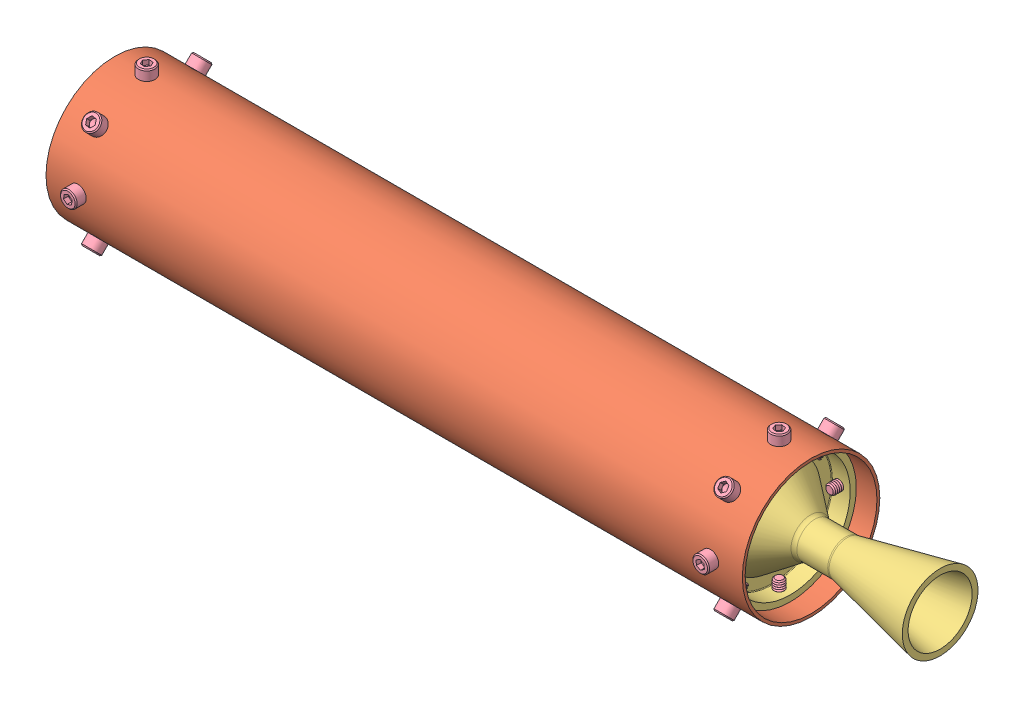
SolidWorks assembly Montagem1, configuration Valor predeterminado. Lengths in mm.
Overall size (286.03 54.66 54.66).
19 component instances, 4 part files, 37 mates.
Components (placement in the parent):
- Epoch Bulkhead-1: Epoch Bulkhead [Valor predeterminado] at (-185.2556 8.6887 45.5676) size (13.69 45.57 45.57)
- Epoch Casing-1: Epoch Casing [Valor predeterminado] at (-105.5307 8.6887 45.5676) size (241.3 47.65 47.65)
- Epoch Nozzle-1: Epoch Nozzle [Valor predeterminado] at (74.7918 8.6887 45.5676) size (67.13 45.67 45.67)
- socket head cap screw_ai632comespiral-2: socket head cap screw_ai632comespiral [HX-SHCS 0.138-32x0.25x0.25-S] at (34.2137 28.0142 64.8931) x (0 -0.707107 -0.707107) z (-0.36592 -0.658066 0.658066) size (9.86 5.74 5.74)
- socket head cap screw_ai632comespiral-3: socket head cap screw_ai632comespiral [HX-SHCS 0.138-32x0.25x0.25-S] at (-184.9375 28.0142 26.2421) x (0 -0.707107 0.707107) z (-0.707107 0.5 0.5) size (9.86 5.74 5.74)
- socket head cap screw_ai632comespiral-4: socket head cap screw_ai632comespiral [HX-SHCS 0.138-32x0.25x0.25-S] at (34.2137 8.6887 18.2372) x (0 0 1) z (-0.773525 -0.633766 0) size (9.86 5.74 5.74)
- socket head cap screw_ai632comespiral-5: socket head cap screw_ai632comespiral [HX-SHCS 0.138-32x0.25x0.25-S] at (34.2137 28.0142 26.2421) x (0 -0.707107 0.707107) z (-0.707107 0.5 0.5) size (9.86 5.74 5.74)
- socket head cap screw_ai632comespiral-6: socket head cap screw_ai632comespiral [HX-SHCS 0.138-32x0.25x0.25-S] at (34.2137 -18.6417 45.5676) x (0 1 0) z (-0.155936 0 0.987767) size (9.86 5.74 5.74)
- socket head cap screw_ai632comespiral-7: socket head cap screw_ai632comespiral [HX-SHCS 0.138-32x0.25x0.25-S] at (34.2137 36.0191 45.5676) x (0 -1 0) z (-0.163272 0 0.986581) size (9.86 5.74 5.74)
- socket head cap screw_ai632comespiral-8: socket head cap screw_ai632comespiral [HX-SHCS 0.138-32x0.25x0.25-S] at (34.2137 8.6887 72.898) x (0 0 -1) z (0.442421 0.896807 0) size (9.86 5.74 5.74)
- socket head cap screw_ai632comespiral-9: socket head cap screw_ai632comespiral [HX-SHCS 0.138-32x0.25x0.25-S] at (-184.9375 -18.6417 45.5676) x (0 1 0) z (-0.333471 0 0.94276) size (9.86 5.74 5.74)
- socket head cap screw_ai632comespiral-10: socket head cap screw_ai632comespiral [HX-SHCS 0.138-32x0.25x0.25-S] at (34.2137 -10.6368 26.2421) x (0 0.707107 0.707107) z (-0.686828 -0.513939 0.513939) size (9.86 5.74 5.74)
- socket head cap screw_ai632comespiral-11: socket head cap screw_ai632comespiral [HX-SHCS 0.138-32x0.25x0.25-S] at (34.2137 -10.6368 64.8931) x (0 0.707107 -0.707107) z (0.271558 0.680535 0.680535) size (9.86 5.74 5.74)
- socket head cap screw_ai632comespiral-12: socket head cap screw_ai632comespiral [HX-SHCS 0.138-32x0.25x0.25-S] at (-184.9375 -10.6368 64.8931) x (0 0.707107 -0.707107) z (-0.76182 0.458056 0.458056) size (9.86 5.74 5.74)
- socket head cap screw_ai632comespiral-13: socket head cap screw_ai632comespiral [HX-SHCS 0.138-32x0.25x0.25-S] at (-184.9375 -10.6368 26.2421) x (0 0.707107 0.707107) z (-0.814375 -0.410361 0.410361) size (9.86 5.74 5.74)
- socket head cap screw_ai632comespiral-14: socket head cap screw_ai632comespiral [HX-SHCS 0.138-32x0.25x0.25-S] at (-184.9375 8.6887 18.2372) x (0 0 1) z (-1 0 0) size (9.86 5.74 5.74)
- socket head cap screw_ai632comespiral-15: socket head cap screw_ai632comespiral [HX-SHCS 0.138-32x0.25x0.25-S] at (-184.9375 8.6887 72.898) x (0 0 -1) z (0.339206 -0.940712 0) size (9.86 5.74 5.74)
- socket head cap screw_ai632comespiral-16: socket head cap screw_ai632comespiral [HX-SHCS 0.138-32x0.25x0.25-S] at (-184.9375 28.0142 64.8931) x (0 -0.707107 -0.707107) z (-0.917285 -0.281592 0.281592) size (9.86 5.74 5.74)
- socket head cap screw_ai632comespiral-17: socket head cap screw_ai632comespiral [HX-SHCS 0.138-32x0.25x0.25-S] at (-184.9375 36.0191 45.5676) x (0 -1 0) z (-0.117759 0 0.993042) size (9.86 5.74 5.74)
Mates (geometry in assembly coordinates):
- Concêntrico1: concentric aligned: circle of Epoch Casing-1; circle of Epoch Nozzle-1
- Concêntrico2: concentric aligned: circle of Epoch Bulkhead-1; circle of Epoch Casing-1
- Concêntrico3: concentric aligned: cylinder of Epoch Casing-1 through (34.2137 32.5139 45.5676) axis (0 1 0) radius 1.3526; cylinder of Epoch Nozzle-1 through (34.2137 31.5233 45.5676) axis (0 1 0) radius 1.3526
- Concêntrico4: concentric aligned: cylinder of Epoch Bulkhead-1 through (-184.9375 31.4725 45.5676) axis (0 1 0) radius 1.3526; cylinder of Epoch Casing-1 through (-184.9375 32.5139 45.5676) axis (0 1 0) radius 1.3526
- Paralelo1: parallel aligned: plane of Epoch Casing-1 through (45.2881 32.5139 45.5676) normal (1 0 0); plane of Epoch Nozzle-1 through (38.1253 8.6887 45.5676) normal (1 0 0)
- Concêntrico6: concentric aligned: cylinder of Epoch Casing-1 through (34.2137 32.5139 45.5676) axis (0 1 0) radius 1.3526; cylinder of socket head cap screw_ai632comespiral-7 through (34.2137 67.7691 45.5676) axis (0 1 0) radius 1.7526
- Concêntrico8: concentric aligned: cylinder of Epoch Casing-1 through (34.2137 25.5357 28.7206) axis (0 0.707107 -0.707107) radius 1.3526; cylinder of socket head cap screw_ai632comespiral-5 through (34.2137 50.4649 3.7914) axis (0 0.707107 -0.707107) radius 1.7526
- Concêntrico10: concentric aligned: cylinder of Epoch Nozzle-1 through (34.2137 8.6887 22.733) axis (0 0 -1) radius 1.3526; cylinder of socket head cap screw_ai632comespiral-4 through (34.2137 8.6887 -13.5128) axis (0 0 -1) radius 1.7526
- Concêntrico12: concentric aligned: cylinder of Epoch Nozzle-1 through (34.2137 24.8352 61.7141) axis (0 0.707107 0.707107) radius 1.3526; cylinder of socket head cap screw_ai632comespiral-2 through (34.2137 50.4649 87.3438) axis (0 0.707107 0.707107) radius 1.7526
- Concêntrico14: concentric aligned: cylinder of Epoch Nozzle-1 through (34.2137 8.6887 68.4022) axis (0 0 1) radius 1.3526; cylinder of socket head cap screw_ai632comespiral-8 through (34.2137 8.6887 104.648) axis (0 0 1) radius 1.7526
- Concêntrico18: concentric aligned: cylinder of Epoch Nozzle-1 through (34.2137 -14.1459 45.5676) axis (0 -1 0) radius 1.3526; cylinder of socket head cap screw_ai632comespiral-6 through (34.2137 -50.3917 45.5676) axis (0 -1 0) radius 1.7526
- Concêntrico20: concentric aligned: cylinder of Epoch Nozzle-1 through (34.2137 -7.4578 29.4211) axis (0 -0.707107 -0.707107) radius 1.3526; cylinder of socket head cap screw_ai632comespiral-10 through (34.2137 -33.0874 3.7914) axis (0 -0.707107 -0.707107) radius 1.7526
- Tangente1: tangent anti-aligned: cylinder of Epoch Casing-1 through (-194.4327 8.6887 45.5676) axis (-1 0 0) radius 23.8252; plane of socket head cap screw_ai632comespiral-7 through (37.0454 32.5139 46.0362) normal (0 -1 0)
- Tangente2: tangent anti-aligned: cylinder of Epoch Casing-1 through (-194.4327 8.6887 45.5676) axis (-1 0 0) radius 23.8252; plane of socket head cap screw_ai632comespiral-2 through (36.8849 24.793 63.1572) normal (0 -0.707107 -0.707107)
- Tangente3: tangent anti-aligned: cylinder of Epoch Casing-1 through (-194.4327 8.6887 45.5676) axis (-1 0 0) radius 23.8252; plane of socket head cap screw_ai632comespiral-8 through (31.6397 9.9586 69.3928) normal (0 0 -1)
- Tangente5: tangent anti-aligned: cylinder of Epoch Casing-1 through (-194.4327 8.6887 45.5676) axis (-1 0 0) radius 23.8252; plane of socket head cap screw_ai632comespiral-6 through (31.3786 -15.1365 45.12) normal (0 1 0)
- Tangente6: tangent anti-aligned: cylinder of Epoch Casing-1 through (-194.4327 8.6887 45.5676) axis (-1 0 0) radius 23.8252; plane of socket head cap screw_ai632comespiral-10 through (32.1276 -6.7643 27.3267) normal (0 0.707107 0.707107)
- Tangente7: tangent anti-aligned: cylinder of Epoch Casing-1 through (-194.4327 8.6887 45.5676) axis (-1 0 0) radius 23.8252; plane of socket head cap screw_ai632comespiral-4 through (32.3947 10.9089 21.7424) normal (0 0 1)
- Tangente8: tangent anti-aligned: cylinder of Epoch Casing-1 through (-194.4327 8.6887 45.5676) axis (-1 0 0) radius 23.8252; plane of socket head cap screw_ai632comespiral-5 through (36.2433 26.9708 30.1557) normal (0 -0.707107 0.707107)
- Concêntrico23: concentric aligned: cylinder of Epoch Bulkhead-1 through (-184.9375 -7.4218 61.6782) axis (0 -0.707107 0.707107) radius 1.3526; cylinder of socket head cap screw_ai632comespiral-12 through (-184.9375 -33.0874 87.3438) axis (0 -0.707107 0.707107) radius 1.7526
- Concêntrico25: concentric aligned: cylinder of Epoch Bulkhead-1 through (-184.9375 -14.0951 45.5676) axis (0 -1 0) radius 1.3526; cylinder of socket head cap screw_ai632comespiral-9 through (-184.9375 -50.3917 45.5676) axis (0 -1 0) radius 1.7526
- Concêntrico27: concentric aligned: cylinder of Epoch Casing-1 through (-184.9375 -8.1582 28.7206) axis (0 -0.707107 -0.707107) radius 1.3526; cylinder of socket head cap screw_ai632comespiral-13 through (-184.9375 -33.0874 3.7914) axis (0 -0.707107 -0.707107) radius 1.7526
- Concêntrico29: concentric aligned: cylinder of Epoch Bulkhead-1 through (-184.9375 8.6887 22.7838) axis (0 0 -1) radius 1.3526; cylinder of socket head cap screw_ai632comespiral-14 through (-184.9375 8.6887 -13.5128) axis (0 0 -1) radius 1.7526
- Concêntrico31: concentric aligned: cylinder of Epoch Casing-1 through (-184.9375 25.5357 28.7206) axis (0 0.707107 -0.707107) radius 1.3526; cylinder of socket head cap screw_ai632comespiral-3 through (-184.9375 50.4649 3.7914) axis (0 0.707107 -0.707107) radius 1.7526
- Concêntrico33: concentric aligned: cylinder of Epoch Casing-1 through (-184.9375 32.5139 45.5676) axis (0 1 0) radius 1.3526; cylinder of socket head cap screw_ai632comespiral-17 through (-184.9375 67.7691 45.5676) axis (0 1 0) radius 1.7526
- Concêntrico35: concentric aligned: cylinder of Epoch Casing-1 through (-184.9375 25.5357 62.4146) axis (0 0.707107 0.707107) radius 1.3526; cylinder of socket head cap screw_ai632comespiral-16 through (-184.9375 50.4649 87.3438) axis (0 0.707107 0.707107) radius 1.7526
- Concêntrico37: concentric aligned: cylinder of Epoch Casing-1 through (-184.9375 8.6887 69.3928) axis (0 0 1) radius 1.3526; cylinder of socket head cap screw_ai632comespiral-15 through (-184.9375 8.6887 104.648) axis (0 0 1) radius 1.7526
- Tangente9: tangent anti-aligned: cylinder of Epoch Casing-1 through (-194.4327 8.6887 45.5676) axis (-1 0 0) radius 23.8252; plane of socket head cap screw_ai632comespiral-15 through (-182.2374 9.6623 69.3928) normal (0 0 -1)
- Tangente10: tangent anti-aligned: cylinder of Epoch Casing-1 through (-194.4327 8.6887 45.5676) axis (-1 0 0) radius 23.8252; plane of socket head cap screw_ai632comespiral-12 through (-186.7967 -9.7044 60.8684) normal (0 0.707107 -0.707107)
- Tangente11: tangent anti-aligned: cylinder of Epoch Casing-1 through (-194.4327 8.6887 45.5676) axis (-1 0 0) radius 23.8252; plane of socket head cap screw_ai632comespiral-9 through (-187.6434 -15.1365 44.6105) normal (0 1 0)
- Tangente12: tangent anti-aligned: cylinder of Epoch Casing-1 through (-194.4327 8.6887 45.5676) axis (-1 0 0) radius 23.8252; plane of socket head cap screw_ai632comespiral-13 through (-186.6032 -6.5054 27.0678) normal (0 0.707107 0.707107)
- Tangente13: tangent anti-aligned: cylinder of Epoch Casing-1 through (-194.4327 8.6887 45.5676) axis (-1 0 0) radius 23.8252; plane of socket head cap screw_ai632comespiral-14 through (-184.9375 11.5589 21.7424) normal (0 0 1)
- Tangente14: tangent anti-aligned: cylinder of Epoch Casing-1 through (-194.4327 8.6887 45.5676) axis (-1 0 0) radius 23.8252; plane of socket head cap screw_ai632comespiral-3 through (-182.9079 26.9708 30.1557) normal (0 -0.707107 0.707107)
- Tangente15: tangent anti-aligned: cylinder of Epoch Casing-1 through (-194.4327 8.6887 45.5676) axis (-1 0 0) radius 23.8252; plane of socket head cap screw_ai632comespiral-17 through (-182.0872 32.5139 45.9056) normal (0 -1 0)
- Tangente16: tangent anti-aligned: cylinder of Epoch Casing-1 through (-194.4327 8.6887 45.5676) axis (-1 0 0) radius 23.8252; plane of socket head cap screw_ai632comespiral-16 through (-183.7945 23.674 64.2762) normal (0 -0.707107 -0.707107)
- Concêntrico47: concentric: cylinder of Epoch Casing-1 through (34.2137 -8.1582 62.4146) axis (0 -0.707107 0.707107) radius 1.3526; circle of socket head cap screw_ai632comespiral-11
- Tangente19: tangent anti-aligned: cylinder of Epoch Casing-1 through (-194.4327 8.6887 45.5676) axis (-1 0 0) radius 23.8252; plane of socket head cap screw_ai632comespiral-11 through (31.4514 -7.6071 62.9657) normal (0 0.707107 -0.707107)
